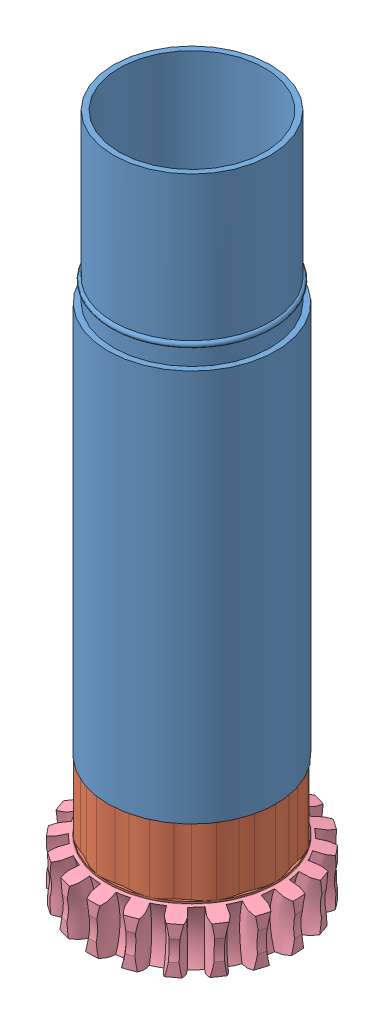
SolidWorks assembly ensamblatge, configuration Default. Lengths in mm.
Overall size (29.18 80.24 29.18).
4 component instances, 4 part files, 7 mates.
Components (placement in the parent):
- tub-1: tub [Default] at (27.9787 19.2173 56.4088) size (19.65 65.33 19.65)
- base-1: base [Default] at (27.9787 10.0473 56.4088) x (0.990946 0 0.134262) z (-0.134262 0 0.990946) size (19.65 63.86 19.65)
- mobil-1: mobil [Default] at (27.9787 19.276 56.4088) x (-0.5 0 0.866025) z (-0.866025 0 -0.5) size (17.03 13.17 17.02)
- glu-stick-pitched-gear-1: glu-stick-pitched-gear [Default] at (27.9787 7.8968 56.4088) x (0.981799 0 -0.189923) z (-0.189923 0 -0.981799) size (24.9 14.97 24.9)
Mates (geometry in assembly coordinates):
- Concentric1: concentric anti-aligned: cylinder of base-1 through (27.9787 73.5823 56.4088) axis (0 -1 0) radius 1.31; cylinder of mobil-1 through (27.9787 19.276 56.4088) axis (0 1 0) radius 0.9825
- Concentric2: concentric anti-aligned: cylinder of tub-1 through (27.9787 19.2173 56.4088) axis (0 1 0) radius 1.31; cylinder of base-1 through (27.9787 24.4573 56.4088) axis (0 -1 0) radius 1.31
- Coincident1: coincident anti-aligned: plane of tub-1 through (27.9787 22.4923 56.4088) normal (0 -1 0); plane of base-1 through (27.9787 22.4923 56.4088) normal (0 1 0)
- Screw1: screw = 5 mm anti-aligned: cylinder of base-1 through (27.9787 73.5823 56.4088) axis (0 -1 0) radius 1.31; cylinder of mobil-1 through (27.9787 19.276 56.4088) axis (0 1 0) radius 0.9825
- Coincident2: coincident anti-aligned: plane of tub-1 through (28.3062 73.5823 48.2213) normal (1 0 0); plane of mobil-1 through (28.3062 19.276 45.4997) normal (-1 0 0)
- Coincident3: coincident anti-aligned: plane of mobil-1 through (27.9787 19.276 56.4088) normal (0 -1 0); plane of glu-stick-pitched-gear-1 through (27.9787 19.276 56.4088) normal (0 1 0)
- Concentric6: concentric anti-aligned: circle of base-1; circle of glu-stick-pitched-gear-1
